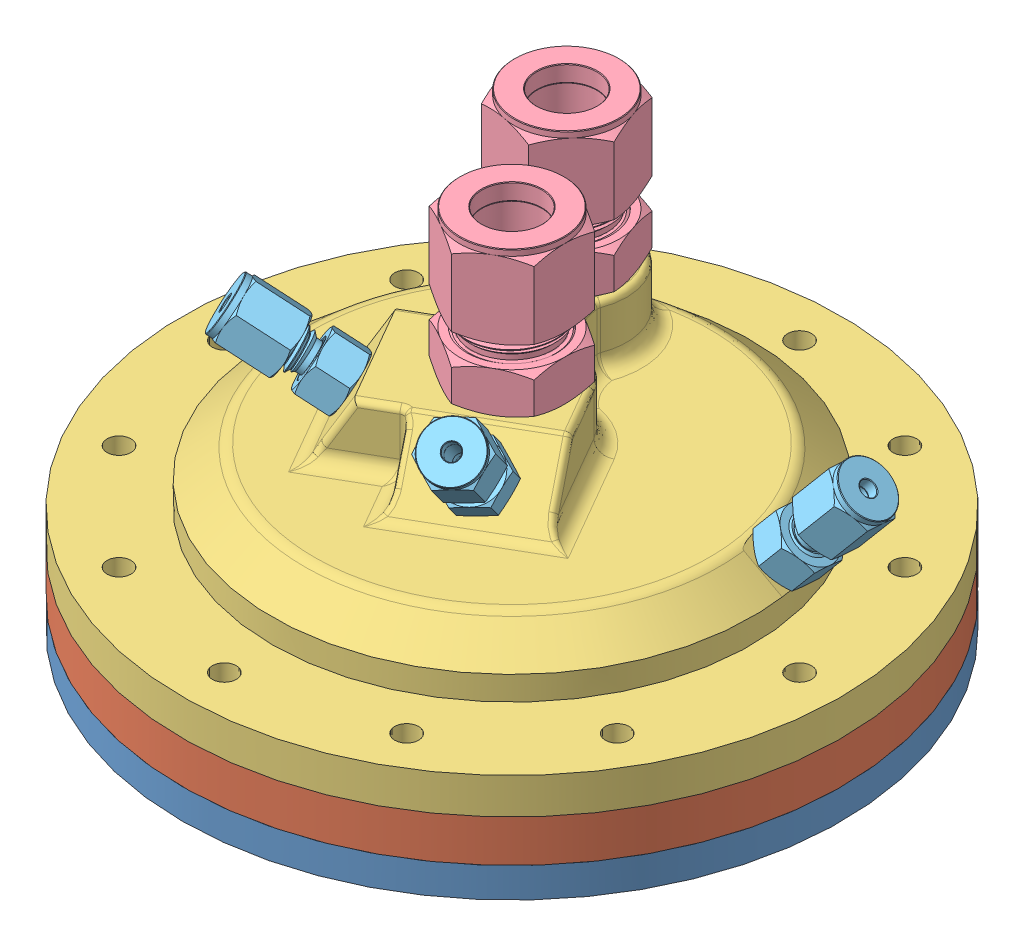
SolidWorks assembly Injector Assembly V6-6-4, configuration Default. Lengths in mm.
Overall size (190.83 77.9 190.83).
8 component instances, 5 part files, 22 mates.
Components (placement in the parent):
- Injector V4-1: Injector V4 [Default] x (1 0 0) z (0 0 -1) size (139.7 6.35 139.7)
- Distribution Plate V4-1: Distribution Plate V4 [Default] x (-0.5 0 -0.866025) z (0.866025 0 -0.5) size (139.7 20.32 139.7)
- Top Plate V4-2: Top Plate V4 [Default] at (0 8.89 0) x (-0.5 0 -0.866025) z (0.866025 0 -0.5) size (139.7 31.93 139.7)
- -8 Swage to ORB-2: -8 Swage to ORB [5182K867] at (0 71.5518 0) x (1 0 0) z (0 1 0) size (22.23 25.66 42.16)
- -8 Swage to ORB-3: -8 Swage to ORB [5182K867] at (-15.875 71.5518 -27.4963) x (0.749656 0 0.661827) z (0 1 0) size (22.23 25.66 42.16)
- -2 Swage to ORB-1: -2 Swage to ORB [5182K861] at (17.5174 50.4527 30.3411) x (-0.48517 0.698333 -0.526252) z (0.353553 0.707107 0.612372) size (11.11 12.83 32)
- -2 Swage to ORB-2: -2 Swage to ORB [5182K861] at (59.5842 41.6339 -15.9655) x (0.780697 -0.623432 0.042956) z (0.620885 0.766044 -0.166366) size (11.11 12.83 32)
- -2 Swage to ORB-3: -2 Swage to ORB [5182K861] at (-38.5262 45.7708 22.2431) x (-0.620533 -0.758533 -0.198916) z (-0.75 0.5 0.433013) size (11.11 12.83 32)
Mates (geometry in assembly coordinates):
- Coincident1: coincident aligned: plane of Injector V4-1 through (0 0 0) normal (0 1 0)
- Coincident2: coincident anti-aligned: plane of Injector V4-1 through (0 0 0) normal (0 0 -1)
- Coincident3: coincident aligned: plane of Injector V4-1 through (0 0 0) normal (1 0 0)
- Coincident7: coincident anti-aligned: plane of Injector V4-1 through (0 0 0) normal (0 1 0); plane of Distribution Plate V4-1 through (0 0 0) normal (0 -1 0)
- Concentric5: concentric anti-aligned: cylinder of Injector V4-1 through (0 -6.35 0) axis (0 1 0) radius 69.85; cylinder of Distribution Plate V4-1 through (0 8.89 0) axis (0 -1 0) radius 69.85
- Concentric8: concentric aligned: cylinder of Distribution Plate V4-1 through (0 0 -60.96) axis (0 1 0) radius 2.54; cylinder of Top Plate V4-1 through (-17.8803 8.89 -58.2788) axis (0 1 0) radius 2.54
- Coincident10: coincident anti-aligned: plane of Distribution Plate V4-1 through (0 8.89 0) normal (0 1 0); plane of Top Plate V4-2 through (3.7866 8.89 2.0121) normal (0 -1 0)
- Concentric12: concentric aligned: cylinder of Injector V4-1 through (0 -6.35 60.96) axis (0 1 0) radius 3.2639; cylinder of Distribution Plate V4-1 through (0 0 60.96) axis (0 1 0) radius 2.54
- Concentric14: concentric anti-aligned: cylinder of Top Plate V4-2 through (31.7284 8.888 -105.5863) axis (0 1 0) radius 12.7; cylinder of -8 Swage to ORB-1 through (31.75 29.6418 0) axis (0 -1 0) radius 5.1562
- Coincident11: coincident anti-aligned: plane of Top Plate V4-2 through (15.875 40.8178 -6.35) normal (0 1 0); plane of -8 Swage to ORB-1 through (31.75 40.8178 -12.8316) normal (0 -1 0)
- Concentric15: concentric aligned: cylinder of Top Plate V4-2 through (3.7866 8.89 2.0121) axis (0 1 0) radius 7.9375; cylinder of -8 Swage to ORB-2 through (3.7866 71.5518 2.0121) axis (0 1 0) radius 6.35
- Coincident12: coincident anti-aligned: plane of Top Plate V4-2 through (3.7866 40.8178 2.0121) normal (0 1 0); plane of -8 Swage to ORB-2 through (3.7866 40.8178 -10.8196) normal (0 -1 0)
- Concentric16: concentric anti-aligned: cylinder of Top Plate V4-2 through (-13.982 8.89 -24.3003) axis (0 1 0) radius 7.9375; cylinder of -8 Swage to ORB-3 through (-13.982 29.6418 -24.3003) axis (0 -1 0) radius 5.1562
- Coincident13: coincident anti-aligned: plane of Top Plate V4-2 through (3.7866 40.8178 2.0121) normal (0 1 0); plane of -8 Swage to ORB-3 through (-5.4897 40.8178 -33.9196) normal (0 -1 0)
- Concentric17: concentric anti-aligned: cylinder of Top Plate V4-2 through (-17.5855 -22.7711 -29.6364) axis (0.395727 0.707107 0.586004) radius 2.794; cylinder of -2 Swage to ORB-1 through (10.7287 27.8224 12.2922) axis (-0.395727 -0.707107 -0.586004) radius 1.1811
- Coincident14: coincident anti-aligned: plane of Top Plate V4-2 through (259.0215 40.8178 -155.0229) normal (0.395727 0.707107 0.586004); plane of -2 Swage to ORB-1 through (9.4352 33.9791 21.7741) normal (-0.395727 -0.707107 -0.586004)
- Concentric18: concentric aligned: cylinder of Top Plate V4-2 through (41.5733 15.7554 -11.0219) axis (0.607654 0.766044 -0.209601) radius 3.4544; cylinder of -2 Swage to ORB-2 through (62.1011 41.6339 -18.1026) axis (0.607654 0.766044 -0.209601) radius 1.5875
- Coincident15: coincident anti-aligned: plane of Top Plate V4-2 through (57.2818 41.1622 74.0544) normal (0.607654 0.766044 -0.209601); plane of -2 Swage to ORB-2 through (47.7385 23.0983 -19.6322) normal (-0.607654 -0.766044 0.209601)
- Concentric19: concentric anti-aligned: cylinder of Top Plate V4-2 through (51.2199 -12.9584 -30.0195) axis (-0.717705 0.5 0.484664) radius 3.4544; cylinder of -2 Swage to ORB-3 through (-10.1112 29.7688 11.3972) axis (0.717705 -0.5 -0.484664) radius 1.1811
- Coincident17: coincident anti-aligned: plane of Top Plate V4-2 through (-52.9089 40.8178 -43.9868) normal (-0.717705 0.5 0.484664); plane of -2 Swage to ORB-3 through (-15.1382 31.6172 21.437) normal (0.717705 -0.5 -0.484664)
- Concentric23: concentric aligned: cylinder of Distribution Plate V4-1 through (30.48 0 -52.7929) axis (0 1 0) radius 2.54; cylinder of Top Plate V4-2 through (30.48 8.89 -52.7929) axis (0 1 0) radius 2.54
- Concentric26: concentric aligned: cylinder of Distribution Plate V4-1 through (0 8.89 0) axis (0 -1 0) radius 69.85; cylinder of Top Plate V4-2 through (0 21.59 0) axis (0 -1 0) radius 69.85
